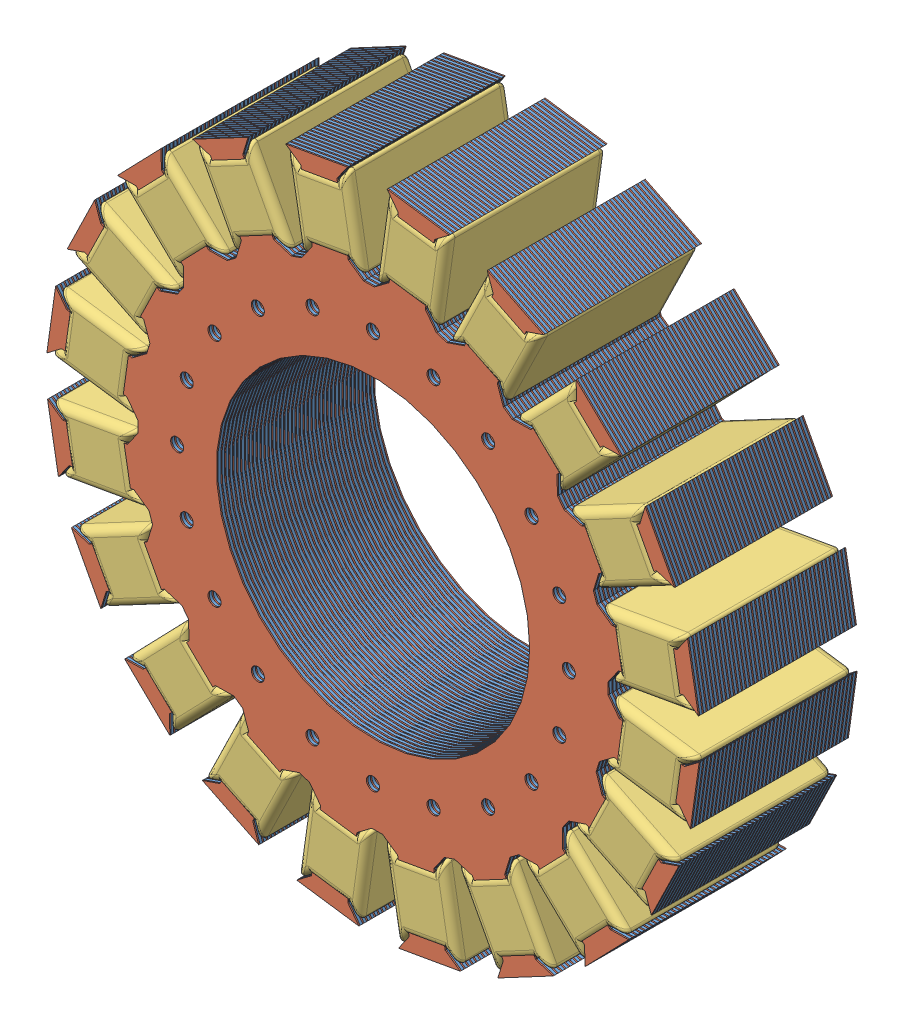
SolidWorks assembly MotorMontaj, configuration Varsayılan. Lengths in mm.
Overall size (314.72 314.72 61.5).
102 component instances, 3 part files, 12 mates.
Components (placement in the parent):
- MotorSacı-1: MotorSacı [Varsayılan] at (-50.8908 -1.9361 249.2651) size (249.77 249.77 1)
- MotorSacıYalıtkanı-1: MotorSacıYalıtkanı [Varsayılan] at (-50.8908 -1.9361 248.7651) x (0.951057 -0.309017 0) z (0 0 1) size (249.77 249.77 0.5)
- MotorSacı-2: MotorSacı [Varsayılan] at (-50.8908 -1.9361 217.7354) size (249.77 249.77 1)
- MotorSacıYalıtkanı-2: MotorSacıYalıtkanı [Varsayılan] at (-50.8908 -1.9361 247.2651) x (0.951057 -0.309017 0) z (0 0 1) size (249.77 249.77 0.5)
- MotorSacıYalıtkanı-3: MotorSacıYalıtkanı [Varsayılan] at (-50.8908 -1.9361 245.7651) x (0.951057 -0.309017 0) z (0 0 1) size (249.77 249.77 0.5)
- MotorSacıYalıtkanı-4: MotorSacıYalıtkanı [Varsayılan] at (-50.8908 -1.9361 244.2651) x (0.951057 -0.309017 0) z (0 0 1) size (249.77 249.77 0.5)
- MotorSacıYalıtkanı-5: MotorSacıYalıtkanı [Varsayılan] at (-50.8908 -1.9361 242.7651) x (0.951057 -0.309017 0) z (0 0 1) size (249.77 249.77 0.5)
- MotorSacıYalıtkanı-6: MotorSacıYalıtkanı [Varsayılan] at (-50.8908 -1.9361 241.2651) x (0.951057 -0.309017 0) z (0 0 1) size (249.77 249.77 0.5)
- MotorSacıYalıtkanı-7: MotorSacıYalıtkanı [Varsayılan] at (-50.8908 -1.9361 239.7651) x (0.951057 -0.309017 0) z (0 0 1) size (249.77 249.77 0.5)
- MotorSacıYalıtkanı-8: MotorSacıYalıtkanı [Varsayılan] at (-50.8908 -1.9361 238.2651) x (0.951057 -0.309017 0) z (0 0 1) size (249.77 249.77 0.5)
- MotorSacıYalıtkanı-9: MotorSacıYalıtkanı [Varsayılan] at (-50.8908 -1.9361 236.7651) x (0.951057 -0.309017 0) z (0 0 1) size (249.77 249.77 0.5)
- MotorSacıYalıtkanı-10: MotorSacıYalıtkanı [Varsayılan] at (-50.8908 -1.9361 235.2651) x (0.951057 -0.309017 0) z (0 0 1) size (249.77 249.77 0.5)
- MotorSacıYalıtkanı-11: MotorSacıYalıtkanı [Varsayılan] at (-50.8908 -1.9361 233.7651) x (0.951057 -0.309017 0) z (0 0 1) size (249.77 249.77 0.5)
- MotorSacıYalıtkanı-12: MotorSacıYalıtkanı [Varsayılan] at (-50.8908 -1.9361 232.2651) x (0.951057 -0.309017 0) z (0 0 1) size (249.77 249.77 0.5)
- MotorSacıYalıtkanı-13: MotorSacıYalıtkanı [Varsayılan] at (-50.8908 -1.9361 230.7651) x (0.951057 -0.309017 0) z (0 0 1) size (249.77 249.77 0.5)
- MotorSacıYalıtkanı-14: MotorSacıYalıtkanı [Varsayılan] at (-50.8908 -1.9361 229.2651) x (0.951057 -0.309017 0) z (0 0 1) size (249.77 249.77 0.5)
- MotorSacıYalıtkanı-15: MotorSacıYalıtkanı [Varsayılan] at (-50.8908 -1.9361 227.7651) x (0.951057 -0.309017 0) z (0 0 1) size (249.77 249.77 0.5)
- MotorSacıYalıtkanı-16: MotorSacıYalıtkanı [Varsayılan] at (-50.8908 -1.9361 226.2651) x (0.951057 -0.309017 0) z (0 0 1) size (249.77 249.77 0.5)
- MotorSacıYalıtkanı-17: MotorSacıYalıtkanı [Varsayılan] at (-50.8908 -1.9361 224.7651) x (0.951057 -0.309017 0) z (0 0 1) size (249.77 249.77 0.5)
- MotorSacıYalıtkanı-18: MotorSacıYalıtkanı [Varsayılan] at (-50.8908 -1.9361 223.2651) x (0.951057 -0.309017 0) z (0 0 1) size (249.77 249.77 0.5)
- MotorSacıYalıtkanı-19: MotorSacıYalıtkanı [Varsayılan] at (-50.8908 -1.9361 221.7651) x (0.951057 -0.309017 0) z (0 0 1) size (249.77 249.77 0.5)
- MotorSacıYalıtkanı-20: MotorSacıYalıtkanı [Varsayılan] at (-50.8908 -1.9361 220.2651) x (0.951057 -0.309017 0) z (0 0 1) size (249.77 249.77 0.5)
- MotorSacıYalıtkanı-21: MotorSacıYalıtkanı [Varsayılan] at (-50.8908 -1.9361 218.7651) x (0.951057 -0.309017 0) z (0 0 1) size (249.77 249.77 0.5)
- MotorSacıYalıtkanı-22: MotorSacıYalıtkanı [Varsayılan] at (-50.8908 -1.9361 217.2651) x (0.951057 -0.309017 0) z (0 0 1) size (249.77 249.77 0.5)
- MotorSacıYalıtkanı-23: MotorSacıYalıtkanı [Varsayılan] at (-50.8908 -1.9361 215.7651) x (0.951057 -0.309017 0) z (0 0 1) size (249.77 249.77 0.5)
- MotorSacıYalıtkanı-24: MotorSacıYalıtkanı [Varsayılan] at (-50.8908 -1.9361 214.2651) x (0.951057 -0.309017 0) z (0 0 1) size (249.77 249.77 0.5)
- MotorSacıYalıtkanı-25: MotorSacıYalıtkanı [Varsayılan] at (-50.8908 -1.9361 212.7651) x (0.951057 -0.309017 0) z (0 0 1) size (249.77 249.77 0.5)
- MotorSacıYalıtkanı-26: MotorSacıYalıtkanı [Varsayılan] at (-50.8908 -1.9361 211.2651) x (0.951057 -0.309017 0) z (0 0 1) size (249.77 249.77 0.5)
- MotorSacıYalıtkanı-27: MotorSacıYalıtkanı [Varsayılan] at (-50.8908 -1.9361 209.7651) x (0.951057 -0.309017 0) z (0 0 1) size (249.77 249.77 0.5)
- MotorSacıYalıtkanı-28: MotorSacıYalıtkanı [Varsayılan] at (-50.8908 -1.9361 208.2651) x (0.951057 -0.309017 0) z (0 0 1) size (249.77 249.77 0.5)
- MotorSacıYalıtkanı-29: MotorSacıYalıtkanı [Varsayılan] at (-50.8908 -1.9361 206.7651) x (0.951057 -0.309017 0) z (0 0 1) size (249.77 249.77 0.5)
- MotorSacıYalıtkanı-30: MotorSacıYalıtkanı [Varsayılan] at (-50.8908 -1.9361 205.2651) x (0.951057 -0.309017 0) z (0 0 1) size (249.77 249.77 0.5)
- MotorSacıYalıtkanı-31: MotorSacıYalıtkanı [Varsayılan] at (-50.8908 -1.9361 203.7651) x (0.951057 -0.309017 0) z (0 0 1) size (249.77 249.77 0.5)
- MotorSacıYalıtkanı-32: MotorSacıYalıtkanı [Varsayılan] at (-50.8908 -1.9361 202.2651) x (0.951057 -0.309017 0) z (0 0 1) size (249.77 249.77 0.5)
- MotorSacıYalıtkanı-33: MotorSacıYalıtkanı [Varsayılan] at (-50.8908 -1.9361 200.7651) x (0.951057 -0.309017 0) z (0 0 1) size (249.77 249.77 0.5)
- MotorSacıYalıtkanı-34: MotorSacıYalıtkanı [Varsayılan] at (-50.8908 -1.9361 199.2651) x (0.951057 -0.309017 0) z (0 0 1) size (249.77 249.77 0.5)
- MotorSacıYalıtkanı-35: MotorSacıYalıtkanı [Varsayılan] at (-50.8908 -1.9361 197.7651) x (0.951057 -0.309017 0) z (0 0 1) size (249.77 249.77 0.5)
- MotorSacıYalıtkanı-36: MotorSacıYalıtkanı [Varsayılan] at (-50.8908 -1.9361 196.2651) x (0.951057 -0.309017 0) z (0 0 1) size (249.77 249.77 0.5)
- MotorSacıYalıtkanı-37: MotorSacıYalıtkanı [Varsayılan] at (-50.8908 -1.9361 194.7651) x (0.951057 -0.309017 0) z (0 0 1) size (249.77 249.77 0.5)
- MotorSacıYalıtkanı-38: MotorSacıYalıtkanı [Varsayılan] at (-50.8908 -1.9361 193.2651) x (0.951057 -0.309017 0) z (0 0 1) size (249.77 249.77 0.5)
- MotorSacıYalıtkanı-39: MotorSacıYalıtkanı [Varsayılan] at (-50.8908 -1.9361 191.7651) x (0.951057 -0.309017 0) z (0 0 1) size (249.77 249.77 0.5)
- MotorSacıYalıtkanı-40: MotorSacıYalıtkanı [Varsayılan] at (-50.8908 -1.9361 190.2651) x (0.951057 -0.309017 0) z (0 0 1) size (249.77 249.77 0.5)
- MotorSacı-3: MotorSacı [Varsayılan] at (-50.8908 -1.9361 247.7651) size (249.77 249.77 1)
- MotorSacı-4: MotorSacı [Varsayılan] at (-50.8908 -1.9361 246.2651) size (249.77 249.77 1)
- MotorSacı-5: MotorSacı [Varsayılan] at (-50.8908 -1.9361 244.7651) size (249.77 249.77 1)
- MotorSacı-6: MotorSacı [Varsayılan] at (-50.8908 -1.9361 243.2651) size (249.77 249.77 1)
- MotorSacı-7: MotorSacı [Varsayılan] at (-50.8908 -1.9361 241.7651) size (249.77 249.77 1)
- MotorSacı-8: MotorSacı [Varsayılan] at (-50.8908 -1.9361 240.2651) size (249.77 249.77 1)
- MotorSacı-9: MotorSacı [Varsayılan] at (-50.8908 -1.9361 238.7651) size (249.77 249.77 1)
- MotorSacı-10: MotorSacı [Varsayılan] at (-50.8908 -1.9361 237.2651) size (249.77 249.77 1)
- MotorSacı-11: MotorSacı [Varsayılan] at (-50.8908 -1.9361 235.7651) size (249.77 249.77 1)
- MotorSacı-12: MotorSacı [Varsayılan] at (-50.8908 -1.9361 234.2651) size (249.77 249.77 1)
- MotorSacı-13: MotorSacı [Varsayılan] at (-50.8908 -1.9361 232.7651) size (249.77 249.77 1)
- MotorSacı-14: MotorSacı [Varsayılan] at (-50.8908 -1.9361 231.2651) size (249.77 249.77 1)
- MotorSacı-15: MotorSacı [Varsayılan] at (-50.8908 -1.9361 229.7651) size (249.77 249.77 1)
- MotorSacı-16: MotorSacı [Varsayılan] at (-50.8908 -1.9361 228.2651) size (249.77 249.77 1)
- MotorSacı-17: MotorSacı [Varsayılan] at (-50.8908 -1.9361 226.7651) size (249.77 249.77 1)
- MotorSacı-18: MotorSacı [Varsayılan] at (-50.8908 -1.9361 225.2651) size (249.77 249.77 1)
- MotorSacı-19: MotorSacı [Varsayılan] at (-50.8908 -1.9361 223.7651) size (249.77 249.77 1)
- MotorSacı-20: MotorSacı [Varsayılan] at (-50.8908 -1.9361 222.2651) size (249.77 249.77 1)
- MotorSacı-21: MotorSacı [Varsayılan] at (-50.8908 -1.9361 220.7651) size (249.77 249.77 1)
- MotorSacı-22: MotorSacı [Varsayılan] at (-50.8908 -1.9361 219.2651) size (249.77 249.77 1)
- MotorSacı-23: MotorSacı [Varsayılan] at (-50.8908 -1.9361 217.7651) size (249.77 249.77 1)
- MotorSacı-24: MotorSacı [Varsayılan] at (-50.8908 -1.9361 216.2651) size (249.77 249.77 1)
- MotorSacı-25: MotorSacı [Varsayılan] at (-50.8908 -1.9361 214.7651) size (249.77 249.77 1)
- MotorSacı-26: MotorSacı [Varsayılan] at (-50.8908 -1.9361 213.2651) size (249.77 249.77 1)
- MotorSacı-27: MotorSacı [Varsayılan] at (-50.8908 -1.9361 211.7651) size (249.77 249.77 1)
- MotorSacı-28: MotorSacı [Varsayılan] at (-50.8908 -1.9361 210.2651) size (249.77 249.77 1)
- MotorSacı-29: MotorSacı [Varsayılan] at (-50.8908 -1.9361 208.7651) size (249.77 249.77 1)
- MotorSacı-30: MotorSacı [Varsayılan] at (-50.8908 -1.9361 207.2651) size (249.77 249.77 1)
- MotorSacı-31: MotorSacı [Varsayılan] at (-50.8908 -1.9361 205.7651) size (249.77 249.77 1)
- MotorSacı-32: MotorSacı [Varsayılan] at (-50.8908 -1.9361 204.2651) size (249.77 249.77 1)
- MotorSacı-33: MotorSacı [Varsayılan] at (-50.8908 -1.9361 202.7651) size (249.77 249.77 1)
- MotorSacı-34: MotorSacı [Varsayılan] at (-50.8908 -1.9361 201.2651) size (249.77 249.77 1)
- MotorSacı-35: MotorSacı [Varsayılan] at (-50.8908 -1.9361 199.7651) size (249.77 249.77 1)
- MotorSacı-36: MotorSacı [Varsayılan] at (-50.8908 -1.9361 198.2651) size (249.77 249.77 1)
- MotorSacı-37: MotorSacı [Varsayılan] at (-50.8908 -1.9361 196.7651) size (249.77 249.77 1)
- MotorSacı-38: MotorSacı [Varsayılan] at (-50.8908 -1.9361 195.2651) size (249.77 249.77 1)
- MotorSacı-39: MotorSacı [Varsayılan] at (-50.8908 -1.9361 193.7651) size (249.77 249.77 1)
- MotorSacı-40: MotorSacı [Varsayılan] at (-50.8908 -1.9361 192.2651) size (249.77 249.77 1)
- MotorSacı-41: MotorSacı [Varsayılan] at (-50.8908 -1.9361 190.7651) size (249.77 249.77 1)
- MotorSacıYalıtkanı-41: MotorSacıYalıtkanı [Varsayılan] at (-50.8908 -1.9361 250.2651) size (249.77 249.77 0.5)
- bobin-3: bobin [Varsayılan] at (-156.6591 12.9287 189.7651) x (0 1 0) z (0 0 1) size (28.05 35.17 61.5)
- bobin-4: bobin [Varsayılan] at (-146.889 44.8854 189.7651) x (0.309017 0.951057 0) z (0 0 1) size (28.05 35.17 61.5)
- bobin-5: bobin [Varsayılan] at (-127.7219 72.2589 189.7651) x (0.587785 0.809017 0) z (0 0 1) size (28.05 35.17 61.5)
- bobin-6: bobin [Varsayılan] at (-101.034 92.3696 189.7651) x (0.809017 0.587785 0) z (0 0 1) size (28.05 35.17 61.5)
- bobin-7: bobin [Varsayılan] at (-69.4377 103.2491 189.7651) x (0.951057 0.309017 0) z (0 0 1) size (28.05 35.17 61.5)
- bobin-8: bobin [Varsayılan] at (-36.026 103.8323 189.7651) size (28.05 35.17 61.5)
- bobin-9: bobin [Varsayılan] at (-4.0693 94.0622 189.7651) x (0.951057 -0.309017 0) z (0 0 1) size (28.05 35.17 61.5)
- bobin-10: bobin [Varsayılan] at (23.3042 74.895 189.7651) x (0.809017 -0.587785 0) z (0 0 1) size (28.05 35.17 61.5)
- bobin-11: bobin [Varsayılan] at (43.4149 48.2072 189.7651) x (0.587785 -0.809017 0) z (0 0 1) size (28.05 35.17 61.5)
- bobin-12: bobin [Varsayılan] at (54.2944 16.6109 189.7651) x (0.309017 -0.951057 0) z (0 0 1) size (28.05 35.17 61.5)
- bobin-13: bobin [Varsayılan] at (54.8776 -16.8008 189.7651) x (0 -1 0) z (0 0 1) size (28.05 35.17 61.5)
- bobin-14: bobin [Varsayılan] at (45.1075 -48.7575 189.7651) x (-0.309017 -0.951057 0) z (0 0 1) size (28.05 35.17 61.5)
- bobin-15: bobin [Varsayılan] at (25.9403 -76.131 189.7651) x (-0.587785 -0.809017 0) z (0 0 1) size (28.05 35.17 61.5)
- bobin-16: bobin [Varsayılan] at (-0.7475 -96.2418 189.7651) x (-0.809017 -0.587785 0) z (0 0 1) size (28.05 35.17 61.5)
- bobin-17: bobin [Varsayılan] at (-32.3438 -107.1212 189.7651) x (-0.951057 -0.309017 0) z (0 0 1) size (28.05 35.17 61.5)
- bobin-18: bobin [Varsayılan] at (-65.7555 -107.7044 189.7651) x (-1 0 0) z (0 0 1) size (28.05 35.17 61.5)
- bobin-19: bobin [Varsayılan] at (-97.7122 -97.9343 189.7651) x (-0.951057 0.309017 0) z (0 0 1) size (28.05 35.17 61.5)
- bobin-20: bobin [Varsayılan] at (-125.0857 -78.7672 189.7651) x (-0.809017 0.587785 0) z (0 0 1) size (28.05 35.17 61.5)
- bobin-21: bobin [Varsayılan] at (-145.1965 -52.0793 189.7651) x (-0.587785 0.809017 0) z (0 0 1) size (28.05 35.17 61.5)
- bobin-22: bobin [Varsayılan] at (-156.0759 -20.483 189.7651) x (-0.309017 0.951057 0) z (0 0 1) size (28.05 35.17 61.5)
Mates (geometry in assembly coordinates):
- Eş Merkezli1: concentric anti-aligned: circle of MotorSacı-1; circle of MotorSacıYalıtkanı-1
- Eş Merkezli2: concentric anti-aligned: circle of MotorSacı-1; circle of MotorSacıYalıtkanı-1
- Çakışık3: coincident anti-aligned: plane of MotorSacı-1 through (-50.8908 -1.9361 249.2651) normal (0 0 -1); plane of MotorSacıYalıtkanı-1 through (-50.8908 -1.9361 249.2651) normal (0 0 1)
- Eş Merkezli4: concentric aligned: circle of MotorSacıYalıtkanı-1; circle of MotorSacı-2
- Eş Merkezli5: concentric aligned: circle of MotorSacı-1; circle of MotorSacı-2
- Eş Merkezli6: concentric anti-aligned: circle of MotorSacı-1; circle of MotorSacıYalıtkanı-41
- Eş Merkezli7: concentric anti-aligned: circle of MotorSacı-1; circle of MotorSacıYalıtkanı-41
- Eş Merkezli8: concentric anti-aligned: circle of MotorSacı-1; circle of MotorSacıYalıtkanı-41
- Çakışık12: coincident anti-aligned: plane of MotorSacı-1 through (-50.8908 -1.9361 250.2651) normal (0 0 1); plane of MotorSacıYalıtkanı-41 through (-50.8908 -1.9361 250.2651) normal (0 0 -1)
- Çakışık20: coincident aligned: line of MotorSacı-3 through (-170.1261 7.7374 248.7651) axis (0 0 -1); line of bobin-3 through (-170.1261 7.7374 248.2651) axis (0 0 -1)
- Çakışık21: coincident aligned: line of MotorSacı-27 through (-168.1735 21.6309 212.7651) axis (0 0 -1); line of bobin-3 through (-168.1735 21.6309 248.2651) axis (0 0 -1)
- Genişlik1: width anti-aligned: plane of bobin-3 through (-156.6591 12.9287 251.2651) normal (0 0 1); plane of bobin-3 through (-156.6591 12.9287 189.7651) normal (0 0 -1); plane of MotorSacıYalıtkanı-40 through (-50.8908 -1.9361 190.2651) normal (0 0 -1); plane of MotorSacıYalıtkanı-41 through (-50.8908 -1.9361 250.7651) normal (0 0 1)
